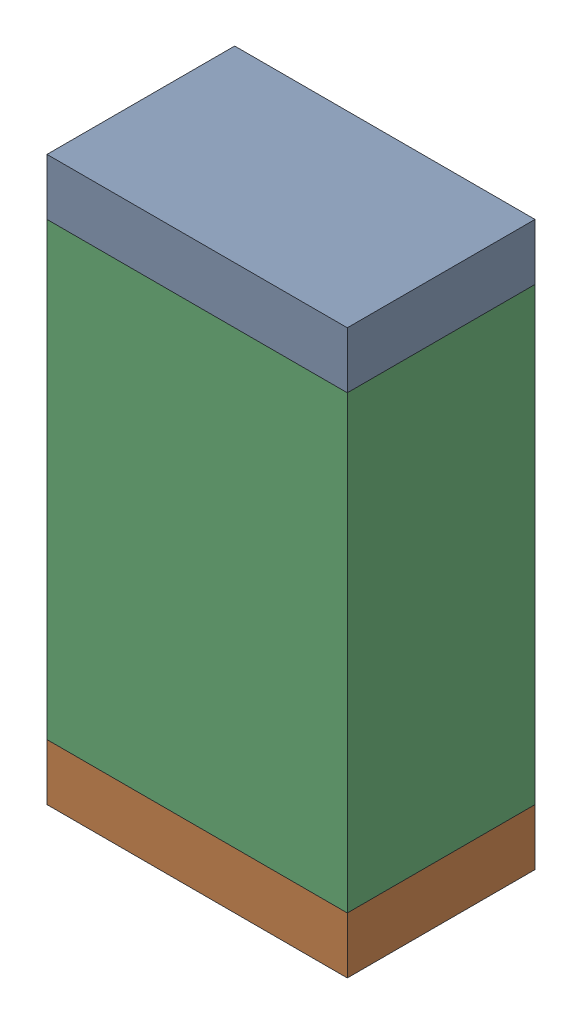
SolidWorks assembly R29, configuration Default. Lengths in mm.
Overall size (0.8 1.5 0.5).
6 component instances, 2 part files, 0 mates.
Components (placement in the parent):
- 810156592-1: 810156592 [Default] at (117.95 48.875 0) size (0.8 0.15 0.5)
  - Extruded_7-1: Extruded_7 [Default] at origin size (0.8 0.15 0.5)
- 810156592-2: 810156592 [Default] at (117.95 47.525 0) size (0.8 0.15 0.5)
  - Extruded_7-1: Extruded_7 [Default] at origin size (0.8 0.15 0.5)
- 810156976-1: 810156976 [Default] at (117.95 48.2 0) size (0.8 1.2 0.5)
  - Extruded_6-1: Extruded_6 [Default] at origin size (0.8 1.2 0.5)
